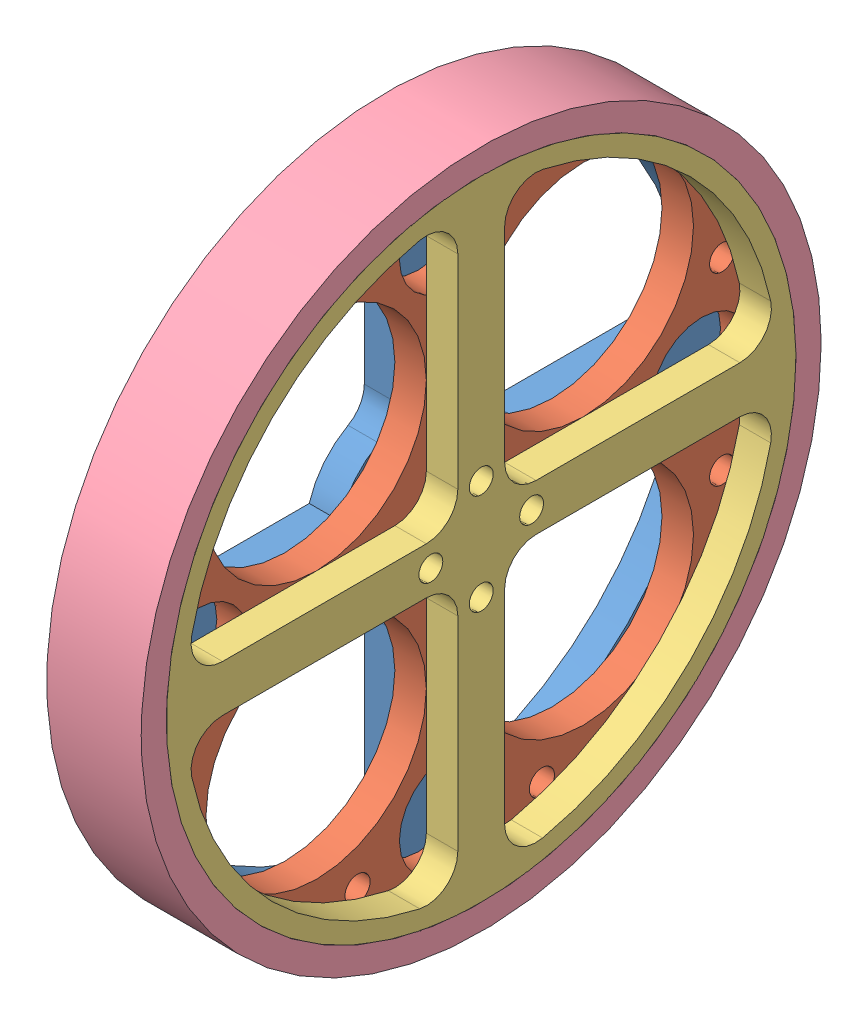
SolidWorks assembly Hjulasm, configuration Default. Lengths in mm.
Overall size (15 141.42 141.42).
4 component instances, 4 part files, 9 mates.
Components (placement in the parent):
- kuggmall-2-1: kuggmall-2 [Default] at (-28.6998 14.9449 0.6594) size (4.88 100 100)
- Hjulbas-1: Hjulbas [Default] at (-18.0622 14.9449 0.6594) x (0 0.707107 -0.707107) z (1 0 0) size (100 100 5)
- Hjul_topp-1: Hjul_topp [Default] at (-13.0622 14.9449 0.6594) x (0 0.707107 -0.707107) z (1 0 0) size (100 100 5)
- Gummirem-1: Gummirem [Default] at (-8.0622 14.9449 0.6594) x (0 0 1) z (-1 0 0) size (108 108 15)
Mates (geometry in assembly coordinates):
- Concentric1: concentric anti-aligned: cylinder of kuggmall-2-1 through (-59.6889 14.9449 0.6594) axis (1 0 0) radius 13; cylinder of Hjulbas-1 through (-13.0622 14.9449 0.6594) axis (-1 0 0) radius 50
- Coincident1: coincident anti-aligned: plane of kuggmall-2-1 through (-18.0622 14.9449 0.6594) normal (1 0 0); plane of Hjulbas-1 through (-18.0622 14.9449 0.6594) normal (-1 0 0)
- InPlace1: in place: plane of ? through (-13.0622 14.9449 0.6594) normal (1 0 0); plane of ? through (-13.0622 0 0) normal (1 0 0); moOrthogonalPlaneRef_w of ? through (-13.0622 14.9449 0.6594) normal (1 0 0); line of ? through (-55 -13.0622 0) axis (0 0 1); plane of ? through (-13.0622 14.9449 0.6594) normal (1 0 0); plane of ? through (-13.0622 0 0) normal (0 0 -1); plane of Hjulbas-1 through (-13.0622 14.9449 0.6594) normal (1 0 0); unknown of Hjul_topp-1
- Coincident2: coincident aligned: plane of Hjulbas-1; plane of Hjul_topp-1
- Coincident3: coincident aligned: moOrthogonalPlaneRef_w of Hjulbas-1; plane of Hjul_topp-1 through (-13.0622 14.9449 0.6594) normal (0 0.707107 0.707107)
- Coincident4: coincident anti-aligned: moOrthogonalPlaneRef_w of Hjulbas-1 through (-13.0622 14.9449 0.6594) axis (0 -0.707107 0.707107); plane of Hjul_topp-1 through (-13.0622 14.9449 0.6594) normal (0 0.707107 -0.707107)
- Concentric2: concentric anti-aligned: cylinder of kuggmall-2-1 through (-18.0622 6.9449 0.6594) axis (1 0 0) radius 1.9; cylinder of Hjulbas-1 through (-13.0622 6.9449 0.6594) axis (-1 0 0) radius 1.9
- Concentric3: concentric anti-aligned: cylinder of kuggmall-2-1 through (-18.0518 14.9449 0.6594) axis (-1 0 0) radius 50; cylinder of Gummirem-1 through (-23.0622 14.9449 0.6594) axis (1 0 0) radius 50
- Coincident5: coincident aligned: plane of Hjul_topp-1 through (-8.0622 14.9449 0.6594) normal (1 0 0); plane of Gummirem-1 through (-8.0622 14.9449 0.6594) normal (1 0 0)
